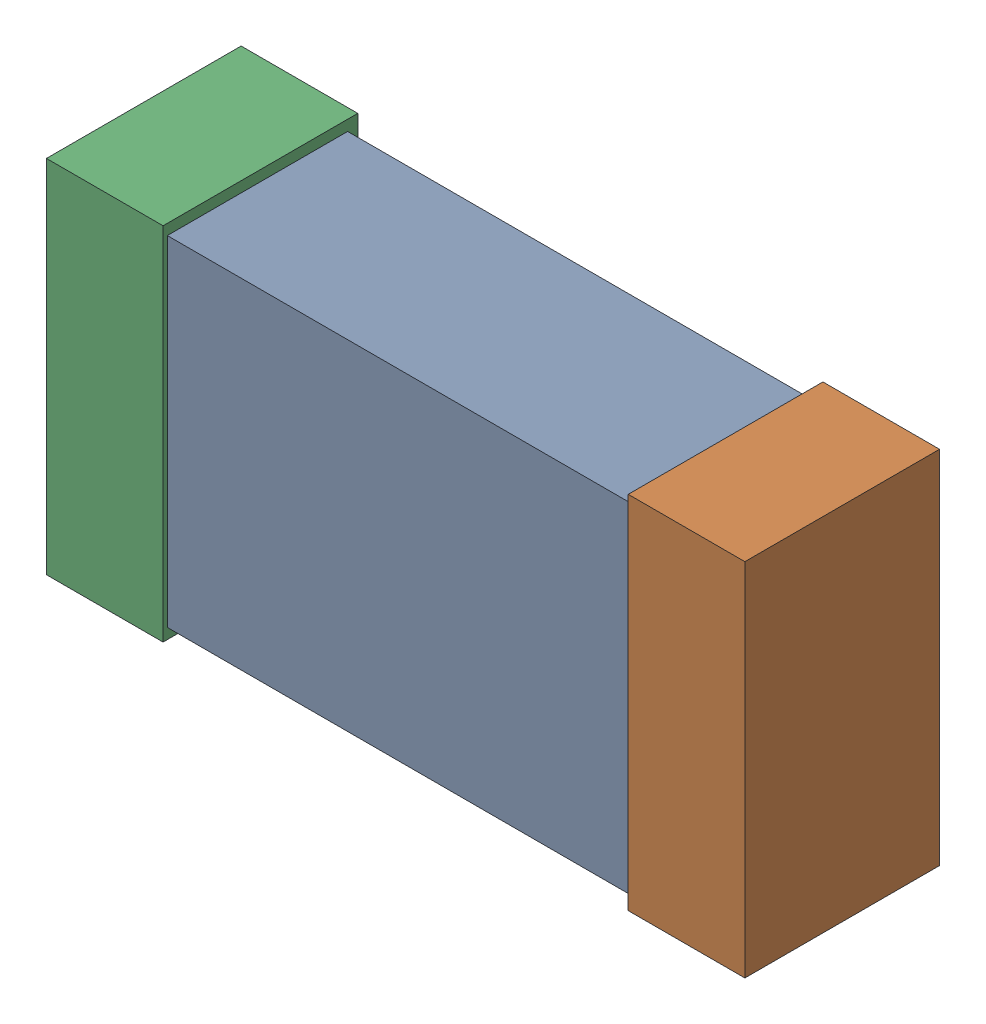
SolidWorks assembly R31, configuration Default. Lengths in mm.
Overall size (1.65 0.85 0.46).
6 component instances, 2 part files, 0 mates.
Components (placement in the parent):
- 432120720_25-1: 432120720_25 [Default] at (24.1649 15.953 0.025) size (1.5 0.8 0.42)
  - Extruded (12)-1: Extruded (12) [Default] at origin size (1.5 0.8 0.42)
- 432120464_52-1: 432120464_52 [Default] at (24.8507 15.953 0.001) size (0.28 0.85 0.46)
  - Extruded (11)-1: Extruded (11) [Default] at origin size (0.28 0.85 0.46)
- 432120464_53-1: 432120464_53 [Default] at (23.4792 15.953 0.001) size (0.28 0.85 0.46)
  - Extruded (11)-1: Extruded (11) [Default] at origin size (0.28 0.85 0.46)
